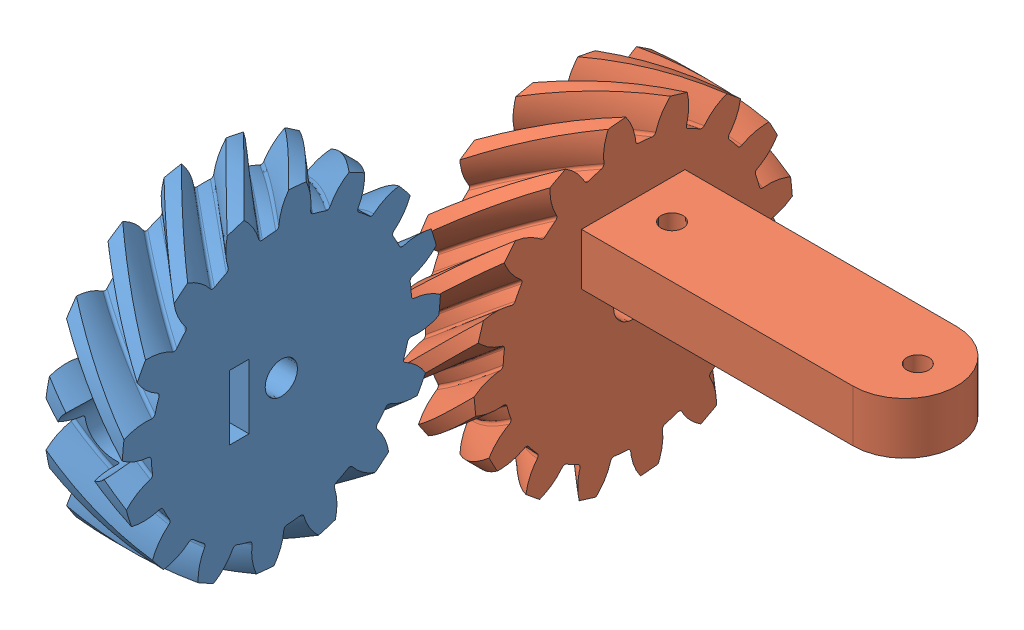
SolidWorks assembly cogAssembly, configuration Default. Lengths in mm.
Overall size (65.88 61.86 99.86).
2 component instances, 2 part files, 0 mates.
Components (placement in the parent):
- motorGear-1: motorGear [ISO - RH Helical gear 2M 16T 45HA 14.5PA 12FW ---16A75H50L5.0N] at (0.3762 6.0973 -28.6394) size (12 49.42 49.34)
- sensorGear-4: sensorGear [ISO - LH Helical gear 2M 16T 45HA 14.5PA 12FW ---16A75H50L5.0N] at (4.2539 -6.3408 -79.1584) size (62 49.42 49.42)
